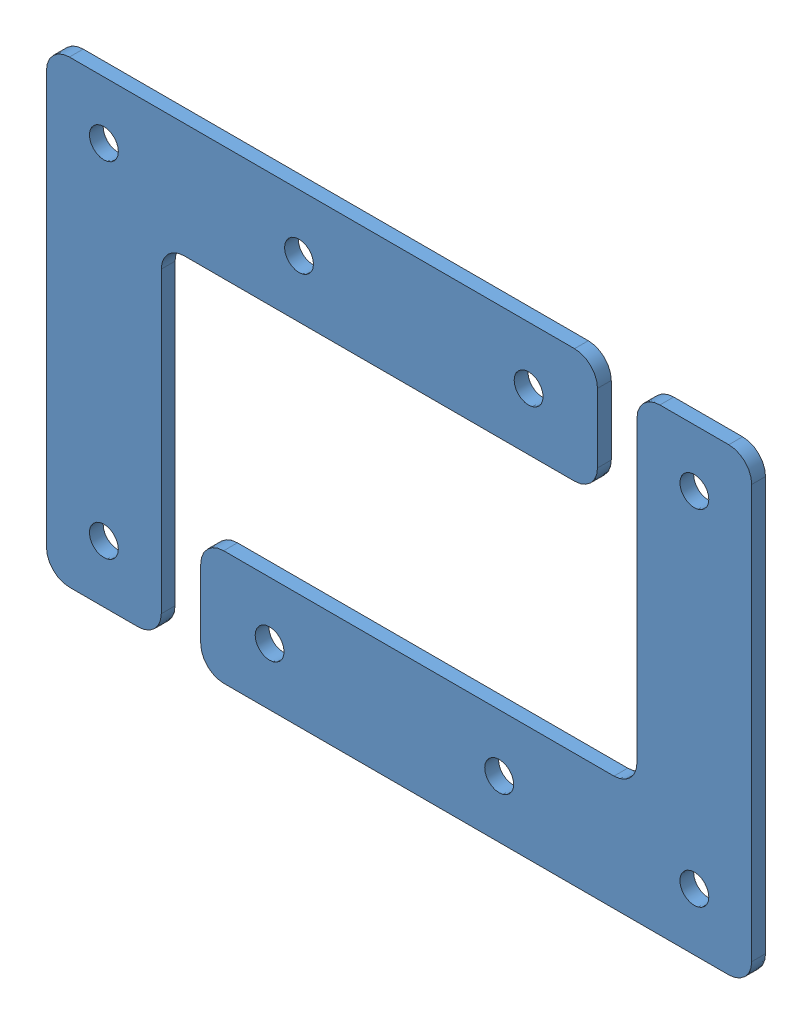
SolidWorks assembly Сборка4, configuration По умолчанию. Lengths in mm.
Overall size (154.91 100 4.32).
2 component instances, 1 part files, 4 mates.
Components (placement in the parent):
- Деталь5-1: Деталь5 [По умолчанию] at origin size (120 100 3)
- Деталь5-2: Деталь5 [По умолчанию] at (154.9125 -100 1.3199) x (-1 0 0) z (0 0 1) size (120 100 3)
Mates (geometry in assembly coordinates):
- Расстояние1: distance = 10 mm: line of Деталь5-1 through (120 -20 3) axis (0 1 0); line of Деталь5-2 through (129.9125 -5 4.3199) axis (0 -1 0)
- Расстояние2: distance = 10 mm: line of Деталь5-2 through (34.9125 -80 4.3199) axis (0 -1 0); line of Деталь5-1 through (25 -95 3) axis (0 1 0)
- Параллельность2: parallel: plane of Деталь5-1 through (0 0 3) normal (0 0 1); plane of Деталь5-2 through (154.9125 -99.3726 4.3199) normal (0 0 1)
- Совпадение8: coincident aligned: plane of Деталь5-1 through (0 0 3) normal (0 1 0); plane of Деталь5-2 through (154.9125 0 4.3199) normal (0 1 0)
